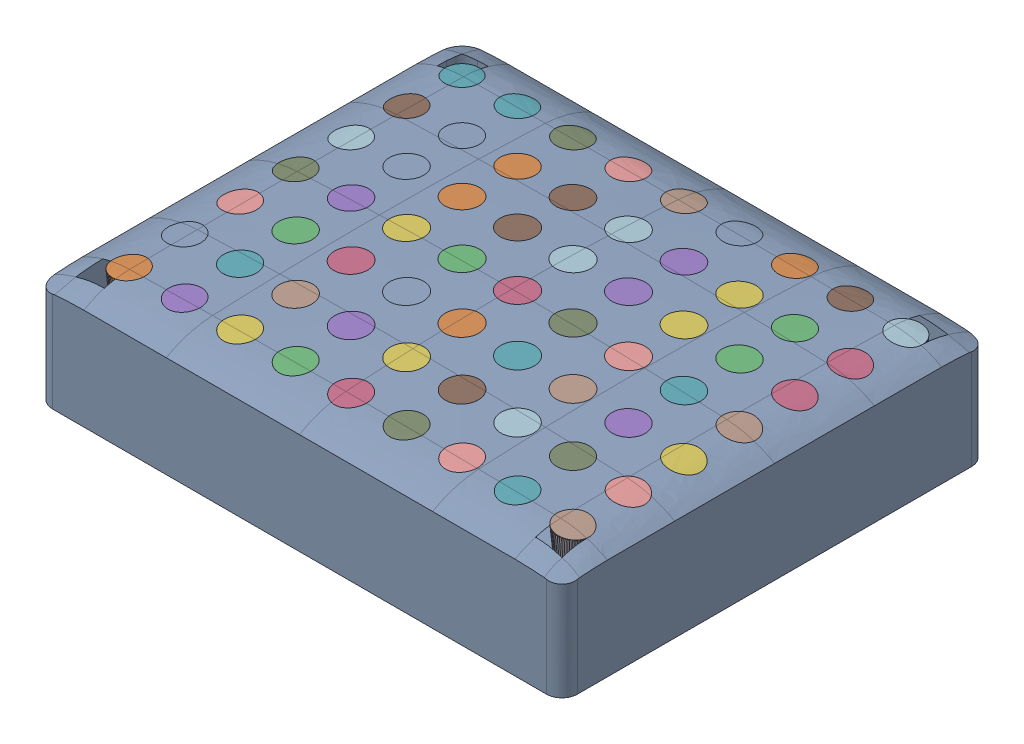
SolidWorks assembly 中间过程, configuration 默认. Lengths in mm.
Overall size (23.8 5.49 19.29).
3 component instances, 3 part files, 4 mates.
Components (placement in the parent):
- InsideSkin_2mm-1: InsideSkin_2mm [默认] at origin size (23.8 5.49 19.29)
- markerTopTip-1: markerTopTip [默认] at (-10.075 22.5 -8.075) x (1 0 0) z (0 -1 0) size (21.2 16.2 0.4)
- Pinmarker2mm_1-1: Pinmarker2mm_1 [默认] at origin size (21.57 1.99 16.56)
Mates (geometry in assembly coordinates):
- 同心1: concentric anti-aligned: cylinder of markerTopTip-1 through (-10.075 22.1 6.925) axis (0 1 0) radius 0.6; cone of Pinmarker1mm_1-1 through (-10.075 22.5 6.925) axis (0 -1 0)
- 重合1: coincident anti-aligned: plane of markerTopTip-1 through (-10.075 22.5 6.925) normal (0 1 0); plane of Pinmarker1mm_1-1 through (-10.075 22.5 6.925) normal (0 -1 0)
- 重合2: coordinate: point of Pinmarker1mm_1-1
- 重合3: coordinate: unknown of InsideSkin-1
